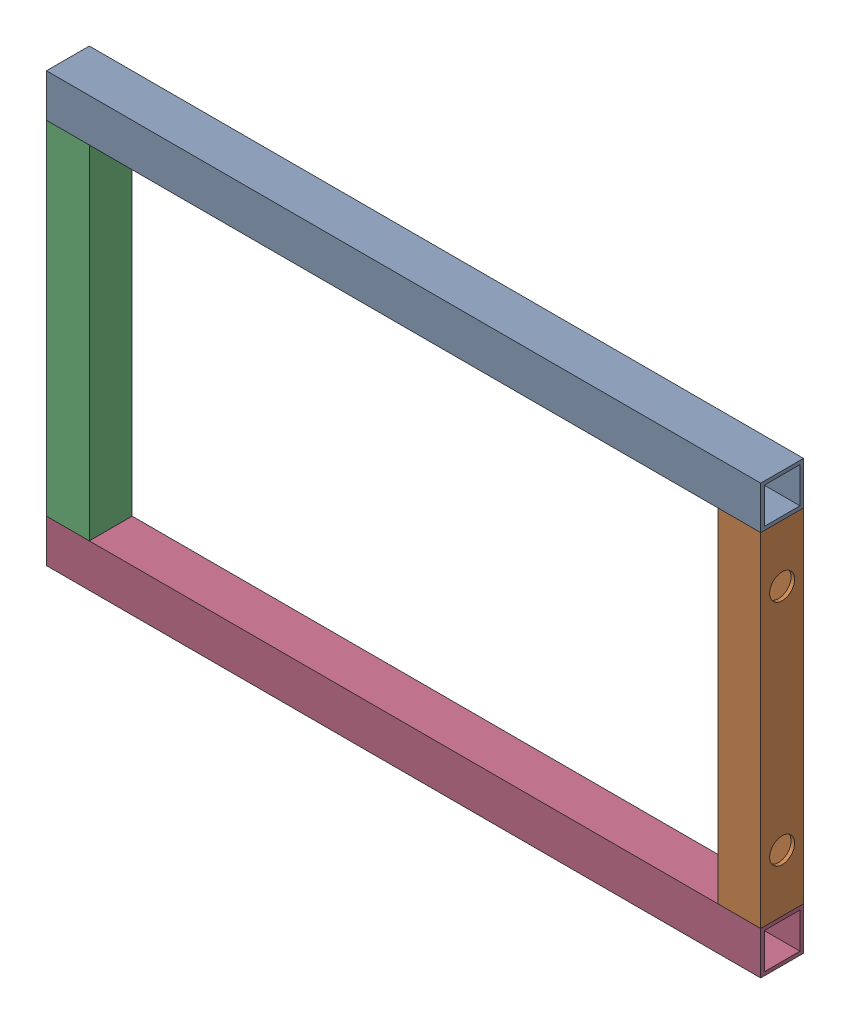
SolidWorks assembly GE-16037_ASM, configuration Default. Lengths in mm.
Overall size (635 381 38.1).
4 component instances, 3 part files, 0 mates.
Components (placement in the parent):
- GE-16037-01-1: GE-16037-01 [Default] at origin size (635 38.1 38.1)
- GE-16037-02-1: GE-16037-02 [Default] at (298.45 -171.45 0) x (0 -1 0) z (0 0 -1) size (304.8 38.1 38.1)
- GE-16037-03-1: GE-16037-03 [Default] at (-298.45 -171.45 0) x (0 -1 0) z (0 0 1) size (304.8 38.1 38.1)
- GE-16037-01-2: GE-16037-01 [Default] at (0 -342.9 0) size (635 38.1 38.1)
